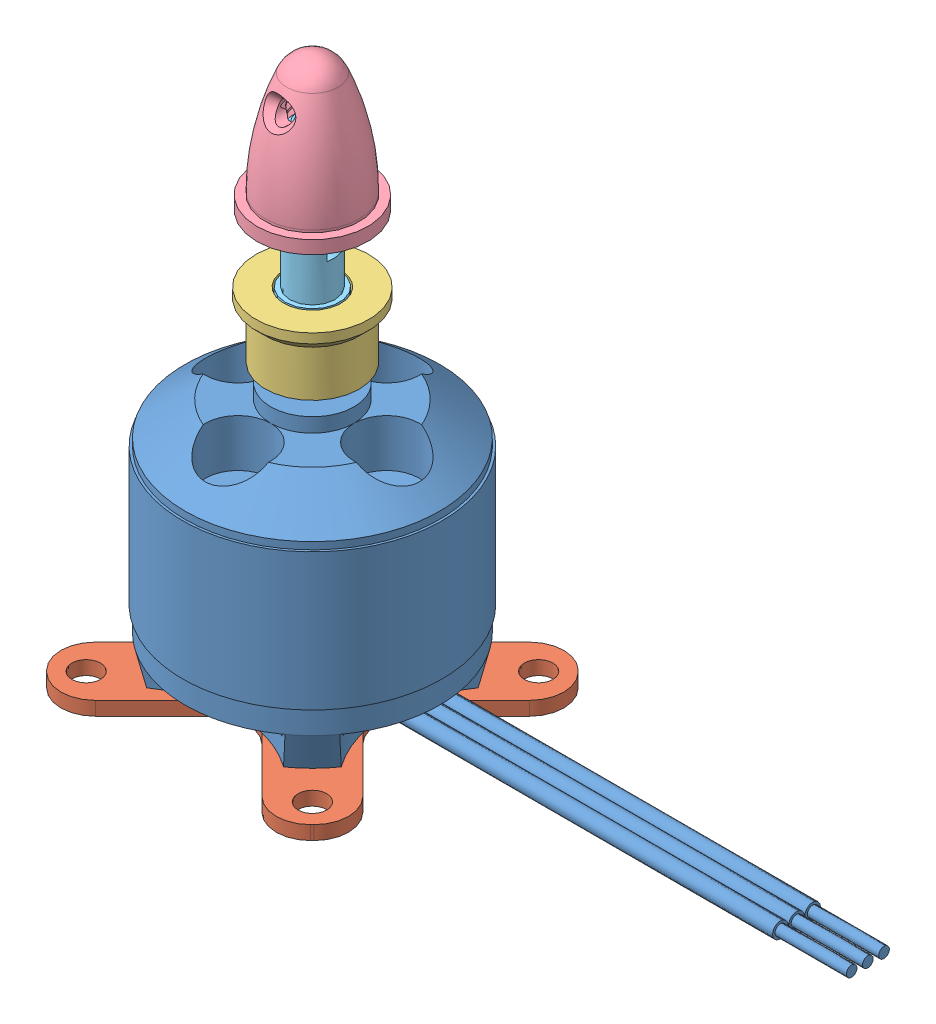
SolidWorks assembly BLDC_A2212_13T_1000KV_Assemly, configuration Default. Lengths in mm.
Overall size (87.69 59.44 56.76).
5 component instances, 5 part files, 11 mates.
Components (placement in the parent):
- BLDC_A2212_13T_1000KV-1: BLDC_A2212_13T_1000KV [Default] at origin size (73.15 40.13 27.69)
- BLDC_A2212_13T_1000KV_MountPlate-1: BLDC_A2212_13T_1000KV_MountPlate [Default] at (0 -26.67 0) x (-0.707107 0 -0.707107) z (-0.707107 0 0.707107) size (40.13 1.47 40.13)
- BLDC_A2212_13T_1000KV_PropCollar-1: BLDC_A2212_13T_1000KV_PropCollar [Default] at (0 8.8646 0) x (0.997679 0 0.068095) z (0.068095 0 -0.997679) size (12.06 6.96 12.06)
- BLDC_A2212_13T_1000KV_PropNut-1: BLDC_A2212_13T_1000KV_PropNut [Default] at (0 16.0097 0) x (-0.117252 0 0.993102) z (-0.993102 0 -0.117252) size (11.84 14.81 11.84)
- BLDC_A2212_13T_1000KV_PropThread-1: BLDC_A2212_13T_1000KV_PropThread [Default] at (0 1.905 0) size (7.91 22.53 7.91)
Mates (geometry in assembly coordinates):
- Coincident3: coincident anti-aligned: plane of BLDC_A2212_13T_1000KV-1 through (12.7 -26.67 0) normal (0 -1 0); plane of BLDC_A2212_13T_1000KV_MountPlate-1 through (11.6743 -26.67 11.4947) normal (0 1 0)
- Concentric1: concentric anti-aligned: cylinder of BLDC_A2212_13T_1000KV-1 through (0 -28.956 0) axis (0 -1 0) radius 1.5557; cylinder of BLDC_A2212_13T_1000KV_PropThread-1 through (0 24.1554 0) axis (0 1 0) radius 2.413
- Coincident4: coincident anti-aligned: plane of BLDC_A2212_13T_1000KV-1 through (0 11.176 0) normal (0 1 0); plane of BLDC_A2212_13T_1000KV_PropThread-1 through (0 11.176 0) normal (0 -1 0)
- Concentric2: concentric aligned: cylinder of BLDC_A2212_13T_1000KV_PropCollar-1 through (0 8.8646 0) axis (0 1 0) radius 5.0038; cylinder of BLDC_A2212_13T_1000KV_PropThread-1 through (0 24.1554 0) axis (0 1 0) radius 2.413
- Concentric3: concentric anti-aligned: cylinder of BLDC_A2212_13T_1000KV-1 through (0 -28.956 0) axis (0 -1 0) radius 1.5557; cylinder of BLDC_A2212_13T_1000KV_PropNut-1 through (0 30.4877 0) axis (0 1 0) radius 5.9182
- LimitDistance1: limit distance = 0 mm aligned: plane of BLDC_A2212_13T_1000KV_PropCollar-1 through (3.8012 1.905 0.2594) normal (0 -1 0); plane of BLDC_A2212_13T_1000KV_PropThread-1 through (1.4732 1.905 0) normal (0 -1 0)
- Screw1: screw = 1 mm aligned: cylinder of BLDC_A2212_13T_1000KV_PropNut-1 through (0 30.4877 0) axis (0 1 0) radius 5.9182; cylinder of BLDC_A2212_13T_1000KV_PropThread-1 through (0 24.1554 0) axis (0 1 0) radius 2.413
- LimitDistance2: limit distance = 14.1047 mm aligned: plane of BLDC_A2212_13T_1000KV_PropNut-1 through (-0.2383 16.0097 2.018) normal (0 -1 0); plane of BLDC_A2212_13T_1000KV_PropThread-1 through (1.4732 1.905 0) normal (0 -1 0)
- Coincident6: coincident aligned: plane of BLDC_A2212_13T_1000KV_PropThread-1 through (0 1.905 0) normal (1 0 0)
- Concentric4: concentric anti-aligned: cylinder of BLDC_A2212_13T_1000KV-1 through (0 -28.956 0) axis (0 -1 0) radius 1.5557; cylinder of BLDC_A2212_13T_1000KV_MountPlate-1 through (0 -28.1432 0) axis (0 1 0) radius 5.08
- Angle1: planar angle = 2.356194 rad: plane of assembly through (0 0 0) normal (0 0 1); plane of assembly; plane of BLDC_A2212_13T_1000KV_MountPlate-1 through (0 -26.67 0) normal (-0.707107 0 -0.707107)
